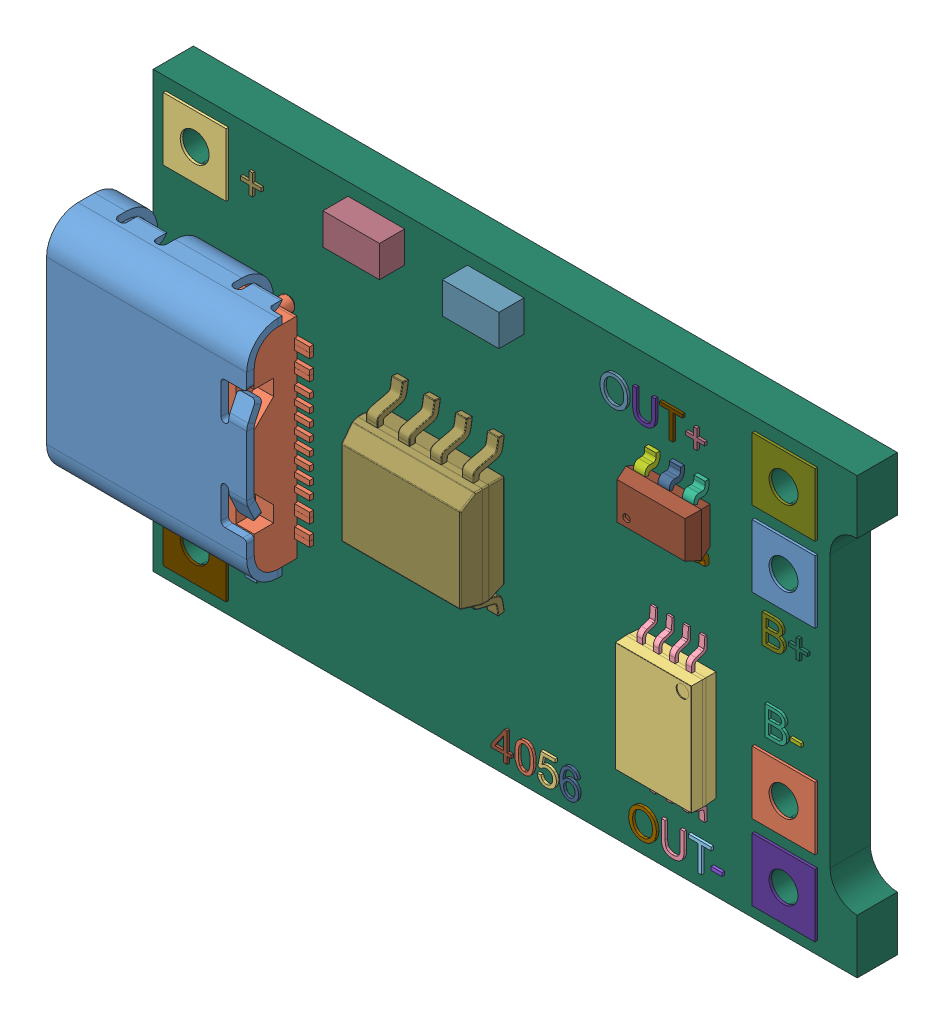
SolidWorks assembly TP4056_Charging_Module_Type_C, configuration Default. Lengths in mm.
Overall size (29.08 17.3 4.86).
58 component instances, 45 part files, 0 mates.
Components (placement in the parent):
- TP4056_Charging_Module_Type_C.step-1: TP4056_Charging_Module_Type_C.step [Default] at origin size (29.08 17.3 4.86)
  - PCB.step-1: PCB.step [Default] at origin size (29.08 17.3 4.86)
    - USB Type C Socket.step-1: USB Type C Socket.step [Default] at (-0.6 8.65 2.7) x (0 -1 0) z (0 0 1) size (8.95 8.56 3.16)
      - Shroud.step-1: Shroud.step [Default] at origin size (8.95 7.96 3.16)
      - Plastic Body & Connector.step-1: Plastic Body & Connector.step [Default] at origin size (8.35 8.12 2.86)
    - Semiconductors.step-1: Semiconductors.step [Default] at origin size (14.71 14.4 2.05)
      - IC 8 Pins SMD Wide.step-1: IC 8 Pins SMD Wide.step [Default] at (19.5 9.2 0) x (1 0 0) z (0 -1 0) size (3.05 1.1 6.42)
        - ATiny45_Body.step-1: ATiny45_Body.step [Default] at (1.4321 2.1436 3.592) size (3.05 1 4.4)
        - ATiny45_Pin.step-1: ATiny45_Pin.step [Default] at (2.4071 2.1421 5.792) x (0 0 1) z (-1 0 0) size (1.01 0.66 0.22)
        - ATiny45_Pin.step-2: ATiny45_Pin.step [Default] at (1.7571 2.1421 1.392) x (0 0 -1) z (1 0 0) size (1.01 0.66 0.22)
        - ATiny45_Pin.step-3: ATiny45_Pin.step [Default] at (1.1071 2.1421 1.392) x (0 0 -1) z (1 0 0) size (1.01 0.66 0.22)
        - ATiny45_Pin.step-4: ATiny45_Pin.step [Default] at (2.4071 2.1421 1.392) x (0 0 -1) z (1 0 0) size (1.01 0.66 0.22)
        - ATiny45_Pin.step-5: ATiny45_Pin.step [Default] at (0.4571 2.1421 1.392) x (0 0 -1) z (1 0 0) size (1.01 0.66 0.22)
        - ATiny45_Pin.step-6: ATiny45_Pin.step [Default] at (1.7571 2.1421 5.792) x (0 0 1) z (-1 0 0) size (1.01 0.66 0.22)
        - ATiny45_Pin.step-7: ATiny45_Pin.step [Default] at (1.1071 2.1421 5.792) x (0 0 1) z (-1 0 0) size (1.01 0.66 0.22)
        - ATiny45_Pin.step-8: ATiny45_Pin.step [Default] at (0.4571 2.1421 5.792) x (0 0 1) z (-1 0 0) size (1.01 0.66 0.22)
      - SC70-6.step-1: SC70-6.step [Default] at (20.5 13.1 1.6) size (3 2.94 1.1)
        - Pin2.step-1: Pin2.step [Default] at origin size (0.45 0.64 0.6)
        - Pin4.step-1: Pin4.step [Default] at origin size (0.45 0.64 0.6)
        - Pin6.step-1: Pin6.step [Default] at origin size (0.45 0.64 0.6)
        - Pin1.step-1: Pin1.step [Default] at origin size (0.45 0.64 0.6)
        - Pin3.step-1: Pin3.step [Default] at origin size (0.45 0.64 0.6)
        - Pin5.step-1: Pin5.step [Default] at origin size (0.45 0.64 0.6)
        - Body.step-1: Body.step [Default] at origin size (3 1.75 1)
      - IC SMD 8 Pins.step-1: IC SMD 8 Pins.step [Default] at (11.85 8.65 1.6) size (5 6.17 2.01)
      - Semiconductors-0.step-1: Semiconductors-0.step [Default] at origin size (2.25 1.25 1)
      - Semiconductors-1.step-1: Semiconductors-1.step [Default] at origin size (2.25 1.25 1)
    - PCB-2.step-1: PCB-2.step [Default] at origin size (28 17.3 1.6)
    - PCB-3.step-1: PCB-3.step [Default] at origin size (0.87 1.15 0.1)
    - PCB-4.step-1: PCB-4.step [Default] at origin size (0.9 1.17 0.1)
    - PCB-5.step-1: PCB-5.step [Default] at origin size (0.91 1.15 0.1)
    - PCB-6.step-1: PCB-6.step [Default] at origin size (0.47 0.15 0.1)
    - PCB-7.step-1: PCB-7.step [Default] at origin size (0.75 1.17 0.1)
    - PCB-8.step-1: PCB-8.step [Default] at origin size (0.76 1.15 0.1)
    - PCB-9.step-1: PCB-9.step [Default] at origin size (0.9 1.17 0.1)
    - PCB-10.step-1: PCB-10.step [Default] at origin size (0.91 1.15 0.1)
    - PCB-11.step-1: PCB-11.step [Default] at origin size (0.87 1.15 0.1)
    - PCB-12.step-1: PCB-12.step [Default] at origin size (0.43 0.14 0.1)
    - PCB-13.step-1: PCB-13.step [Default] at origin size (0.43 0.14 0.1)
    - PCB-14.step-1: PCB-14.step [Default] at origin size (1.1 1.19 0.1)
    - PCB-15.step-1: PCB-15.step [Default] at origin size (0.76 1.17 0.1)
    - PCB-16.step-1: PCB-16.step [Default] at origin size (0.8 1.15 0.1)
    - PCB-17.step-1: PCB-17.step [Default] at origin size (0.83 0.83 0.1)
    - PCB-18.step-1: PCB-18.step [Default] at origin size (0.76 0.76 0.1)
    - PCB-19.step-1: PCB-19.step [Default] at origin size (1.1 1.19 0.1)
    - PCB-20.step-1: PCB-20.step [Default] at origin size (0.76 0.76 0.1)
    - PCB-21.step-1: PCB-21.step [Default] at origin size (2.5 2.5 0.1)
    - PCB-22.step-1: PCB-22.step [Default] at origin size (2.5 2.5 0.1)
    - PCB-23.step-1: PCB-23.step [Default] at origin size (2.5 2.5 0.1)
    - PCB-24.step-1: PCB-24.step [Default] at origin size (2.5 2.5 0.1)
    - PCB-25.step-1: PCB-25.step [Default] at origin size (2.5 2.5 0.1)
    - PCB-26.step-1: PCB-26.step [Default] at origin size (2.5 2.5 0.1)
    - PCB-27.step-1: PCB-27.step [Default] at origin size (2.5 2.5 0.1)
    - PCB-28.step-1: PCB-28.step [Default] at origin size (2.5 2.5 0.1)
    - PCB-29.step-1: PCB-29.step [Default] at origin size (2.5 2.5 0.1)
    - PCB-30.step-1: PCB-30.step [Default] at origin size (2.5 2.5 0.1)
    - PCB-31.step-1: PCB-31.step [Default] at origin size (2.5 2.5 0.1)
    - PCB-32.step-1: PCB-32.step [Default] at origin size (2.5 2.5 0.1)
